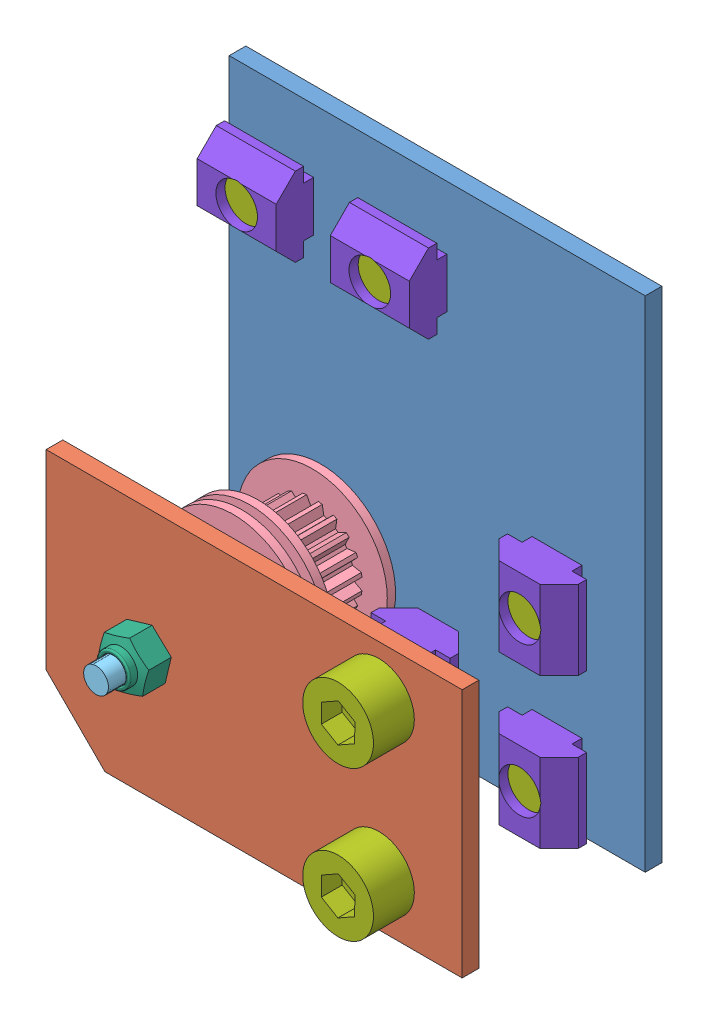
SolidWorks assembly 051XY惰轮组合2, configuration 默认. Lengths in mm.
Overall size (50.24 60 34.91).
21 component instances, 8 part files, 41 mates.
Components (placement in the parent):
- XY惰轮上固定片-1: XY惰轮上固定片 [默认] at (-52.8313 -43.6236 78.5) x (1 0 0) z (0 -1 0) size (50 2 60)
- XY惰轮下固定片-1: XY惰轮下固定片 [默认] at (-52.8313 -43.6236 100.5) x (1 0 0) z (0 -1 0) size (50 2 30)
- M3_6_1尼龙垫片-1: M3_6_1尼龙垫片 [默认] at (-40.8313 -28.6236 100.5) x (0.873789 0.486305 0) z (-0.486305 0.873789 0) size (6 1 6)
- 2GT惰轮6MM20齿3MM孔-带齿-1: 2GT惰轮6MM20齿3MM孔-带齿 [默认] at (-40.8313 -28.6236 99.5) x (0.873789 0.486305 0) z (-0.486305 0.873789 0) size (18 8.5 18)
- M3_6_1尼龙垫片-2: M3_6_1尼龙垫片 [默认] at (-40.8313 -28.6236 91) x (0.873789 0.486305 0) z (-0.486305 0.873789 0) size (6 1 6)
- 2GT惰轮6MM20齿3MM孔-带齿-2: 2GT惰轮6MM20齿3MM孔-带齿 [默认] at (-40.8313 -28.6236 90) x (0.873789 0.486305 0) z (-0.486305 0.873789 0) size (18 8.5 18)
- M3_6_1尼龙垫片-3: M3_6_1尼龙垫片 [默认] at (-40.8313 -28.6236 81.5) x (0.873789 0.486305 0) z (-0.486305 0.873789 0) size (6 1 6)
- M3_30-1: M3_30 [默认] at (-40.8313 -28.6236 108.5) x (1 0 0) z (0 1 0) size (5.5 32.93 5.5)
- M3尼龙螺母-1: M3尼龙螺母 [默认] at (-40.8313 -28.6236 102.5) x (1 0 0) z (0 -1 0) size (6.88 4 6.18)
- M5_6-1: M5_6 [默认] at (-46.8313 6.3764 84.5) x (1 0 0) z (0 1 0) size (8.5 10.91 8.5)
- M5_6-2: M5_6 [默认] at (-30.8313 6.3764 84.5) x (1 0 0) z (0 1 0) size (8.5 10.91 8.5)
- M5_6-3: M5_6 [默认] at (-12.8313 -19.6236 84.5) x (1 0 0) z (0 1 0) size (8.5 10.91 8.5)
- M5_6-4: M5_6 [默认] at (-12.8313 -37.6236 84.5) x (1 0 0) z (0 1 0) size (8.5 10.91 8.5)
- 欧标20M5滑块螺母-1: 欧标20M5滑块螺母 [默认] at (-51.5813 11.1264 85.6) x (1 0 0) z (0 1 0) size (9.5 4.5 9.5)
- 欧标20M5滑块螺母-2: 欧标20M5滑块螺母 [默认] at (-35.5813 11.1264 85.6) x (1 0 0) z (0 1 0) size (9.5 4.5 9.5)
- 欧标20M5滑块螺母-3: 欧标20M5滑块螺母 [默认] at (-17.5813 -24.3736 85.6) x (0 1 0) z (-1 0 0) size (9.5 4.5 9.5)
- 欧标20M5滑块螺母-4: 欧标20M5滑块螺母 [默认] at (-17.5813 -42.3736 85.6) x (0 1 0) z (-1 0 0) size (9.5 4.5 9.5)
- M5_6-5: M5_6 [默认] at (-12.8313 -19.6236 96.5) x (1 0 0) z (0 -1 0) size (8.5 10.91 8.5)
- M5_6-6: M5_6 [默认] at (-12.8313 -37.6236 96.5) x (1 0 0) z (0 -1 0) size (8.5 10.91 8.5)
- 欧标20M5滑块螺母-5: 欧标20M5滑块螺母 [默认] at (-8.0813 -24.3736 95.4) x (0 1 0) z (1 0 0) size (9.5 4.5 9.5)
- 欧标20M5滑块螺母-6: 欧标20M5滑块螺母 [默认] at (-8.0813 -42.3736 95.4) x (0 1 0) z (1 0 0) size (9.5 4.5 9.5)
Mates (geometry in assembly coordinates):
- 重合2: coincident: plane of assembly; plane of assembly; plane of M3_6_1尼龙垫片-1 through (-40.8313 -28.6236 99.5) normal (0 0 -1); plane of 2GT惰轮6MM20齿3MM孔-带齿-1 through (-40.8313 -28.6236 99.5) normal (0 0 1)
- 同心6: concentric: circle of assembly; circle of assembly; circle of M3_6_1尼龙垫片-1; circle of 2GT惰轮6MM20齿3MM孔-带齿-1
- 重合3: coincident: plane of assembly; plane of assembly; plane of 2GT惰轮6MM20齿3MM孔-带齿-1 through (-40.8313 -28.6236 91) normal (0 0 -1); plane of M3_6_1尼龙垫片-2 through (-40.8313 -28.6236 91) normal (0 0 1)
- 同心7: concentric: circle of assembly; circle of assembly; circle of 2GT惰轮6MM20齿3MM孔-带齿-1; circle of M3_6_1尼龙垫片-2
- 重合4: coincident: plane of assembly; plane of assembly; plane of M3_6_1尼龙垫片-2 through (-40.8313 -28.6236 90) normal (0 0 -1); plane of 2GT惰轮6MM20齿3MM孔-带齿-2 through (-40.8313 -28.6236 90) normal (0 0 1)
- 同心8: concentric: circle of assembly; circle of assembly; circle of M3_6_1尼龙垫片-2; circle of 2GT惰轮6MM20齿3MM孔-带齿-2
- 重合5: coincident: plane of assembly; plane of assembly; plane of 2GT惰轮6MM20齿3MM孔-带齿-2 through (-40.8313 -28.6236 81.5) normal (0 0 -1); plane of M3_6_1尼龙垫片-3 through (-40.8313 -28.6236 81.5) normal (0 0 1)
- 同心9: concentric: circle of assembly; circle of assembly; circle of 2GT惰轮6MM20齿3MM孔-带齿-2; circle of M3_6_1尼龙垫片-3
- 重合6: coincident: plane of assembly; plane of assembly; plane of XY惰轮上固定片-1 through (-52.8313 -43.6236 80.5) normal (0 0 1); plane of M3_6_1尼龙垫片-3 through (-40.8313 -28.6236 80.5) normal (0 0 -1)
- 同心16: concentric: circle of assembly; circle of assembly; circle of XY惰轮上固定片-1; circle of M3_6_1尼龙垫片-3
- 同心17: concentric: circle of assembly; circle of assembly; circle of XY惰轮下固定片-1; circle of M3_6_1尼龙垫片-1
- 距离2: distance = 20 mm: plane of assembly; plane of assembly; plane of XY惰轮上固定片-1 through (-52.8313 -43.6236 80.5) normal (0 0 1); plane of XY惰轮下固定片-1 through (-52.8313 -43.6236 100.5) normal (0 0 -1)
- 平行3: parallel: plane of assembly; plane of assembly; plane of XY惰轮上固定片-1 through (-52.8313 -43.6236 80.5) normal (0 -1 0); plane of XY惰轮下固定片-1 through (-52.8313 -43.6236 102.5) normal (0 -1 0)
- 重合7: coincident: plane of assembly; plane of assembly; plane of XY惰轮上固定片-1 through (-52.8313 -43.6236 78.5) normal (0 0 -1); plane of M3_30-1 through (-40.8313 -28.6236 78.5) normal (0 0 1)
- 同心18: concentric: cylinder of assembly; cylinder of assembly; cylinder of XY惰轮上固定片-1 through (-40.8313 -28.6236 78.5) axis (0 0 1) radius 1.75; cylinder of M3_30-1 through (-40.8313 -28.6236 78.5) axis (0 0 1) radius 1.5
- 重合8: coincident: plane of assembly; plane of assembly; plane of XY惰轮上固定片-1 through (-52.8313 -43.6236 78.5) normal (0 0 -1); plane of M5_6-1 through (-46.8313 6.3764 78.5) normal (0 0 1)
- 同心19: concentric: cylinder of assembly; cylinder of assembly; cylinder of XY惰轮上固定片-1 through (-46.8313 6.3764 78.5) axis (0 0 1) radius 2.75; cylinder of M5_6-1 through (-46.8313 6.3764 78.5) axis (0 0 1) radius 2.5
- 重合9: coincident: plane of assembly; plane of assembly; plane of XY惰轮上固定片-1 through (-52.8313 -43.6236 78.5) normal (0 0 -1); plane of M5_6-2 through (-30.8313 6.3764 78.5) normal (0 0 1)
- 同心20: concentric: cylinder of assembly; cylinder of assembly; cylinder of XY惰轮上固定片-1 through (-30.8313 6.3764 78.5) axis (0 0 1) radius 2.75; cylinder of M5_6-2 through (-30.8313 6.3764 78.5) axis (0 0 1) radius 2.5
- 重合10: coincident: plane of assembly; plane of assembly; plane of XY惰轮上固定片-1 through (-52.8313 -43.6236 78.5) normal (0 0 -1); plane of M5_6-3 through (-12.8313 -19.6236 78.5) normal (0 0 1)
- 同心21: concentric: cylinder of assembly; cylinder of assembly; cylinder of XY惰轮上固定片-1 through (-12.8313 -19.6236 78.5) axis (0 0 1) radius 2.75; cylinder of M5_6-3 through (-12.8313 -19.6236 78.5) axis (0 0 1) radius 2.5
- 重合11: coincident: plane of assembly; plane of assembly; plane of XY惰轮上固定片-1 through (-52.8313 -43.6236 78.5) normal (0 0 -1); plane of M5_6-4 through (-12.8313 -37.6236 78.5) normal (0 0 1)
- 同心22: concentric: cylinder of assembly; cylinder of assembly; cylinder of XY惰轮上固定片-1 through (-12.8313 -37.6236 78.5) axis (0 0 1) radius 2.75; cylinder of M5_6-4 through (-12.8313 -37.6236 78.5) axis (0 0 1) radius 2.5
- 同心23: concentric: cylinder of assembly; cylinder of assembly; cylinder of M5_6-3 through (-12.8313 -19.6236 78.5) axis (0 0 1) radius 2.5; cylinder of 欧标20M5滑块螺母-3 through (-12.8313 -19.6236 85.6) axis (0 0 -1) radius 2.5
- 同心24: concentric: cylinder of assembly; cylinder of assembly; cylinder of M5_6-4 through (-12.8313 -37.6236 78.5) axis (0 0 1) radius 2.5; cylinder of 欧标20M5滑块螺母-4 through (-12.8313 -37.6236 85.6) axis (0 0 -1) radius 2.5
- 距离3: distance = 1.8 mm: plane of assembly; plane of assembly; plane of 欧标20M5滑块螺母-4 through (-17.5813 -42.3736 82.3) normal (0 0 -1); plane of XY惰轮上固定片-1 through (-52.8313 -43.6236 80.5) normal (0 0 1)
- 距离4: distance = 1.8 mm: plane of assembly; plane of assembly; plane of XY惰轮上固定片-1 through (-52.8313 -43.6236 80.5) normal (0 0 1); plane of 欧标20M5滑块螺母-3 through (-17.5813 -24.3736 82.3) normal (0 0 -1)
- 同心25: concentric: cylinder of assembly; cylinder of assembly; cylinder of M5_6-2 through (-30.8313 6.3764 78.5) axis (0 0 1) radius 2.5; cylinder of 欧标20M5滑块螺母-2 through (-30.8313 6.3764 85.6) axis (0 0 -1) radius 2.5
- 同心26: concentric: cylinder of assembly; cylinder of assembly; cylinder of M5_6-1 through (-46.8313 6.3764 78.5) axis (0 0 1) radius 2.5; cylinder of 欧标20M5滑块螺母-1 through (-46.8313 6.3764 85.6) axis (0 0 -1) radius 2.5
- 距离5: distance = 1.8 mm: plane of assembly; plane of assembly; plane of XY惰轮上固定片-1 through (-52.8313 -43.6236 80.5) normal (0 0 1); plane of 欧标20M5滑块螺母-2 through (-35.5813 11.1264 82.3) normal (0 0 -1)
- 距离6: distance = 1.8 mm: plane of assembly; plane of assembly; plane of XY惰轮上固定片-1 through (-52.8313 -43.6236 80.5) normal (0 0 1); plane of 欧标20M5滑块螺母-1 through (-51.5813 11.1264 82.3) normal (0 0 -1)
- 重合12: coincident: plane of assembly; plane of assembly; plane of XY惰轮下固定片-1 through (-52.8313 -43.6236 102.5) normal (0 0 1); plane of M3尼龙螺母-1 through (-40.8313 -28.6236 102.5) normal (0 0 -1)
- 同心27: concentric: cylinder of assembly; cylinder of assembly; cylinder of M3_30-1 through (-40.8313 -28.6236 78.5) axis (0 0 1) radius 1.5; cylinder of M3尼龙螺母-1 through (-40.8313 -28.6236 106.5) axis (0 0 -1) radius 1.5
- 重合13: coincident: plane of assembly; plane of assembly; plane of XY惰轮下固定片-1 through (-52.8313 -43.6236 102.5) normal (0 0 1); plane of M5_6-6 through (-12.8313 -37.6236 102.5) normal (0 0 -1)
- 重合14: coincident: plane of assembly; plane of assembly; plane of XY惰轮下固定片-1 through (-52.8313 -43.6236 102.5) normal (0 0 1); plane of M5_6-5 through (-12.8313 -19.6236 102.5) normal (0 0 -1)
- 同心28: concentric: cylinder of assembly; cylinder of assembly; cylinder of XY惰轮下固定片-1 through (-12.8313 -37.6236 100.5) axis (0 0 1) radius 2.75; cylinder of M5_6-6 through (-12.8313 -37.6236 102.5) axis (0 0 -1) radius 2.5
- 同心29: concentric: cylinder of assembly; cylinder of assembly; cylinder of XY惰轮下固定片-1 through (-12.8313 -19.6236 100.5) axis (0 0 1) radius 2.75; cylinder of M5_6-5 through (-12.8313 -19.6236 102.5) axis (0 0 -1) radius 2.5
- 同心30: concentric: cylinder of assembly; cylinder of assembly; cylinder of M5_6-6 through (-12.8313 -37.6236 102.5) axis (0 0 -1) radius 2.5; cylinder of 欧标20M5滑块螺母-6 through (-12.8313 -37.6236 95.4) axis (0 0 1) radius 2.5
- 同心31: concentric: cylinder of assembly; cylinder of assembly; cylinder of M5_6-5 through (-12.8313 -19.6236 102.5) axis (0 0 -1) radius 2.5; cylinder of 欧标20M5滑块螺母-5 through (-12.8313 -19.6236 95.4) axis (0 0 1) radius 2.5
- 距离7: distance = 1.8 mm: plane of assembly; plane of assembly; plane of XY惰轮下固定片-1 through (-52.8313 -43.6236 100.5) normal (0 0 -1); plane of 欧标20M5滑块螺母-6 through (-8.0813 -42.3736 98.7) normal (0 0 1)
- 距离8: distance = 1.8 mm: plane of assembly; plane of assembly; plane of 欧标20M5滑块螺母-5 through (-8.0813 -24.3736 98.7) normal (0 0 1); plane of XY惰轮下固定片-1 through (-52.8313 -43.6236 100.5) normal (0 0 -1)
